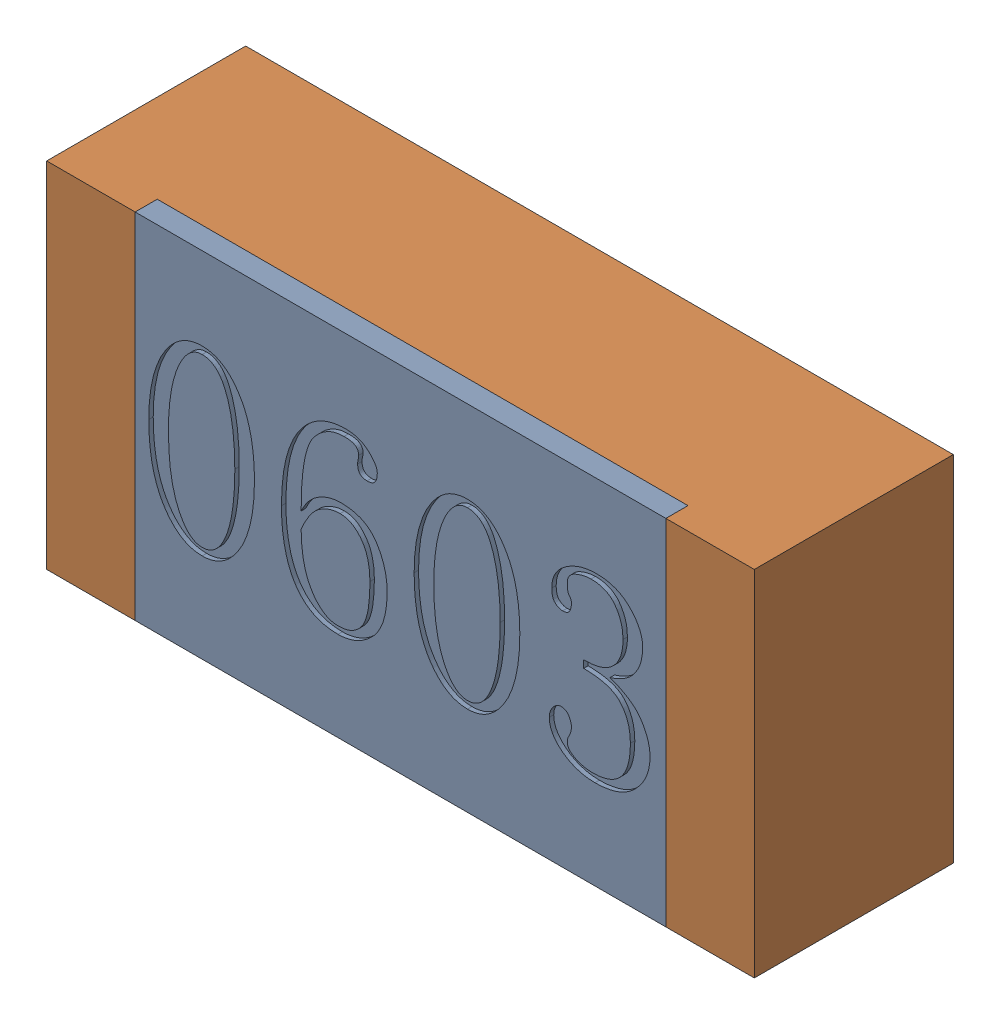
SolidWorks assembly RC1, configuration 默认. Lengths in mm.
Overall size (1.6 0.8 0.45).
3 component instances, 2 part files, 0 mates.
Components (placement in the parent):
- RC1-subassembly-1-1: RC1-subassembly-1 [默认] at (36.5371 12.3191 0) x (1 0 0) z (0 0 1) size (1.6 0.8 0.45)
  - R0603-1: R0603 [默认] at origin size (1.2 0.8 0.05)
  - R0603-1-1: R0603-1 [默认] at origin size (1.6 0.8 0.45)
